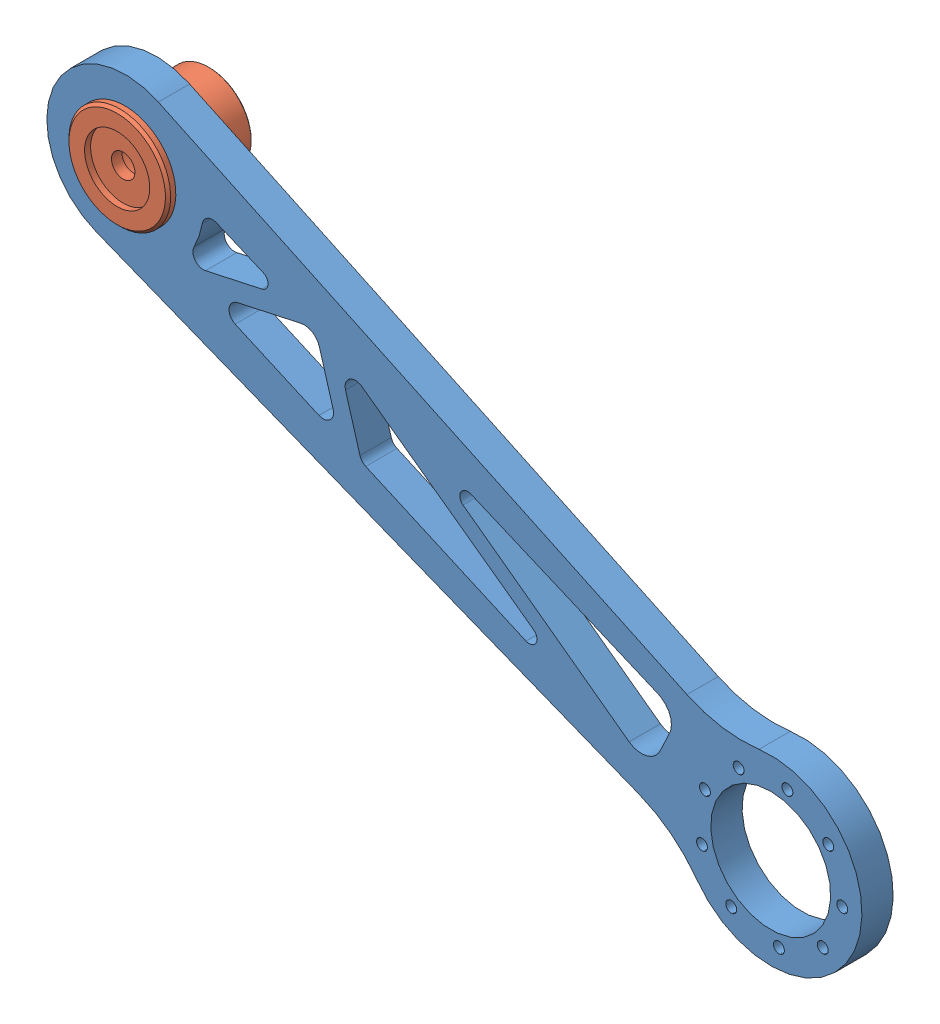
SolidWorks assembly 小腿总装（不带轴承）, configuration 默认. Lengths in mm.
Overall size (335.21 197.45 35.35).
2 component instances, 2 part files, 4 mates.
Components (placement in the parent):
- 小腿mk1mod4-1: 小腿mk1mod4 [默认] at (-443.6471 -218.2829 192.2452) x (0.91753 -0.397667 0) z (0 0 1) size (335 70 12)
- 大螺母-2: 大螺母 [默认] at (-443.6471 -218.2829 171.8952) x (0 0 1) z (-0.73569 -0.677319 0) size (35.35 39 39)
Mates (geometry in assembly coordinates):
- 同心22: concentric anti-aligned: cylinder of 大螺母-2 through (-443.6471 -218.2829 171.8952) axis (0 0 -1) radius 17; cylinder of 小腿mk1mod4-1 through (-443.6471 -218.2829 192.2452) axis (0 0 1) radius 17
- 重合24: coincident anti-aligned: plane of 大螺母-2 through (-454.4842 -206.5119 204.2452) normal (0 0 -1); plane of 小腿mk1mod4-1 through (-443.6471 -218.2829 204.2452) normal (0 0 1)
- 同心23: concentric aligned: cylinder of 小腿mk1mod4-1 through (-443.6471 -218.2829 -192.2452) axis (0 0 1) radius 17; cylinder of 大螺母-2 through (-443.6471 -218.2829 -171.8952) axis (0 0 1) radius 17
- 重合25: coincident anti-aligned: plane of 小腿mk1mod4-1 through (-443.6471 -218.2829 -204.2452) normal (0 0 -1); plane of 大螺母-2 through (-454.4842 -206.5119 -204.2452) normal (0 0 1)
